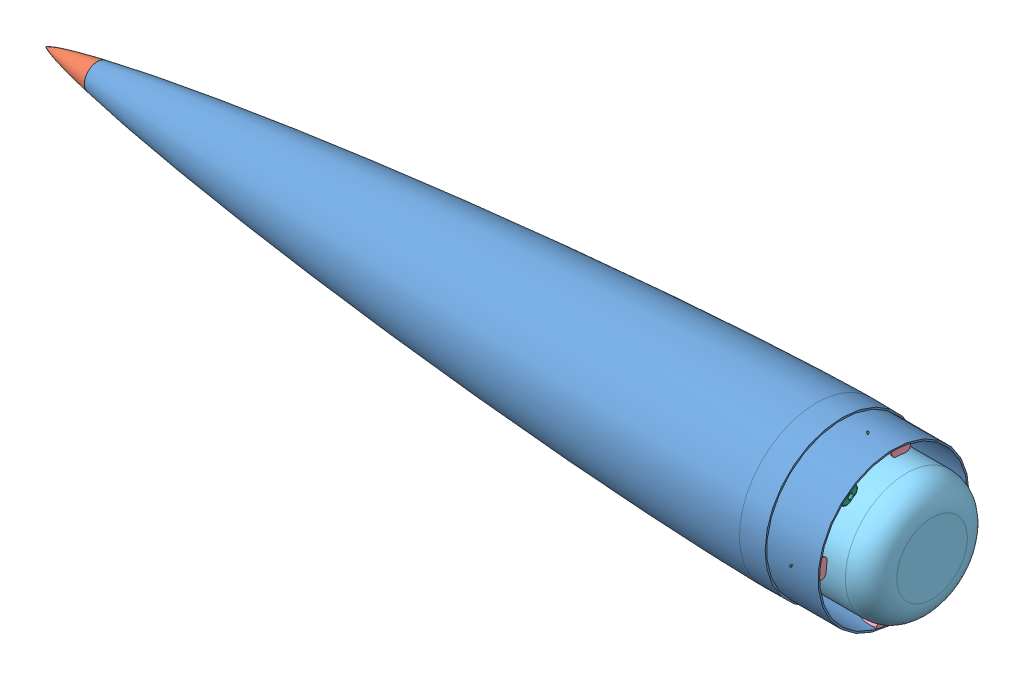
SolidWorks assembly 10003-R03_NOSE_CONE_ASSEMBLY, configuration Default. Lengths in mm.
Overall size (1752.6 337.52 337.52).
9 component instances, 6 part files, 7 mates.
Components (placement in the parent):
- 14015-R03_NOSE_CONE_MAIN_PORTION-1: 14015-R03_NOSE_CONE_MAIN_PORTION [Default] at (-306.7187 919.2546 1145.5242) size (1574.8 304.98 304.98)
- 14016-R02_NOSE_CONE_METAL_TIP-1: 14016-R02_NOSE_CONE_METAL_TIP [Default] at (-306.7187 919.2546 1145.5242) x (1 0 0) z (0 0.723211 0.690628) size (114.3 51.57 51.57)
- 14022-R01_NYLON_SHEAR_PINS-1: 14022-R01_NYLON_SHEAR_PINS [Default] at (1318.8813 919.2546 993.1242) x (0 0 1) z (-0.242152 -0.970238 0) size (8.19 4.11 4.11)
- 14022-R01_NYLON_SHEAR_PINS-2: 14022-R01_NYLON_SHEAR_PINS [Default] at (1318.8813 766.8546 1145.5242) x (0 1 0) z (-0.982149 0 0.188105) size (8.19 4.11 4.11)
- 14022-R01_NYLON_SHEAR_PINS-3: 14022-R01_NYLON_SHEAR_PINS [Default] at (1318.8813 919.2546 1297.9242) x (0 0 -1) z (0.923728 0.383049 0) size (8.19 4.11 4.11)
- 14022-R01_NYLON_SHEAR_PINS-4: 14022-R01_NYLON_SHEAR_PINS [Default] at (1318.8813 1071.6546 1145.5242) x (0 -1 0) z (-0.546944 0 0.837169) size (8.19 4.11 4.11)
- 14017-R02_NOSE_CONE_TABS-1: 14017-R02_NOSE_CONE_TABS [Default] at (1369.6813 915.5518 1291.5273) x (1 0 0) z (0 -0.999679 -0.025353) size (41.17 295.79 295.79)
- 14044-R01_Parachute_Stand-In-1: 14044-R01_Parachute_Stand-In [Default] at (683.8813 919.2546 1145.5242) x (0 0.595063 -0.803679) z (1 0 0) size (241.3 241.3 762)
- 14061-R01_NOSECONE_TETHER_MOUNT-1: 14061-R01_NOSECONE_TETHER_MOUNT [Default] at (1369.6813 1022.5883 1248.7364) x (1 0 0) z (0 -0.70669 0.707523) size (54.18 19.42 43.61)
Mates (geometry in assembly coordinates):
- Coincident1: coincident: circle of 14015-R03_NOSE_CONE_MAIN_PORTION-1; circle of 14016-R02_NOSE_CONE_METAL_TIP-1
- Concentric9: concentric: circle of 14017-R02_NOSE_CONE_TABS-1; circle of 14015-R03_NOSE_CONE_MAIN_PORTION-1
- Coincident2: coincident: plane of 14015-R03_NOSE_CONE_MAIN_PORTION-1 through (1369.6813 919.2546 1145.5242) normal (1 0 0); plane of 14017-R02_NOSE_CONE_TABS-1 through (1369.6813 789.6148 1176.761) normal (1 0 0)
- Concentric10: concentric: circle of 14015-R03_NOSE_CONE_MAIN_PORTION-1; circle of 14044-R01_Parachute_Stand-In-1
- Distance3: distance = 76.2 mm: plane of 14015-R03_NOSE_CONE_MAIN_PORTION-1 through (1369.6813 919.2546 1145.5242) normal (1 0 0); plane of 14044-R01_Parachute_Stand-In-1 through (1445.8813 919.2546 1145.5242) normal (1 0 0)
- Concentric16: concentric: cylinder of 14015-R03_NOSE_CONE_MAIN_PORTION-1 through (-309.8266 919.2546 1145.5242) axis (1 0 0) radius 146.1401; cylinder of 14061-R01_NOSECONE_TETHER_MOUNT-1 through (1369.6813 919.2546 1145.5242) axis (1 0 0) radius 146.05
- Coincident4: coincident: plane of 14015-R03_NOSE_CONE_MAIN_PORTION-1 through (1369.6813 919.2546 1145.5242) normal (1 0 0); plane of 14061-R01_NOSECONE_TETHER_MOUNT-1 through (1369.6813 1032.0278 1210.5453) normal (1 0 0)
